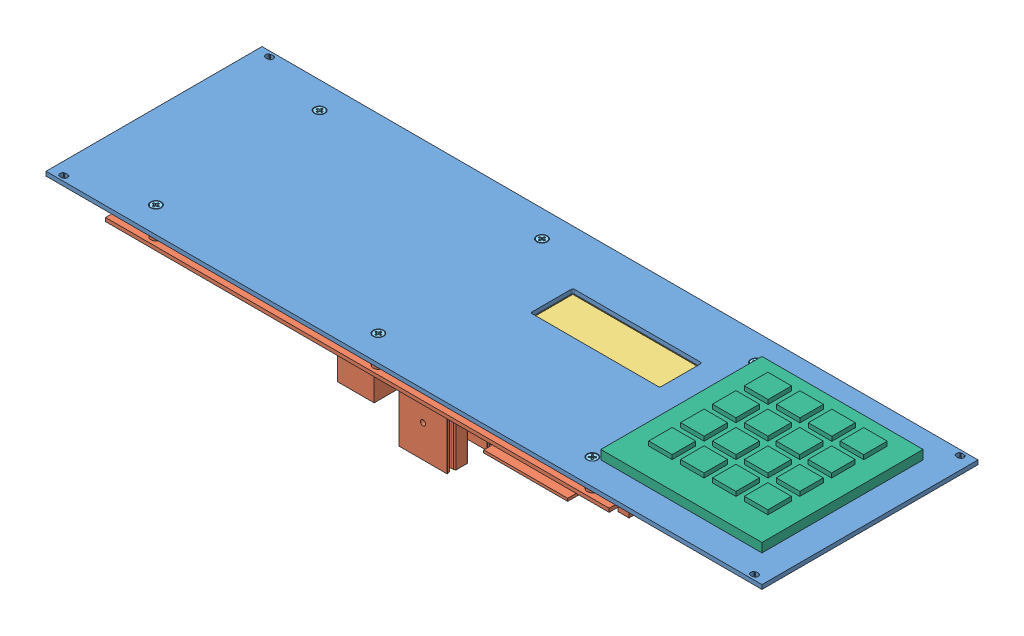
SolidWorks assembly MLA-0387-M5, configuration Default. Lengths in mm.
Overall size (426.52 64.16 128.7).
14 component instances, 6 part files, 28 mates.
Components (placement in the parent):
- MLA-0387-M1-1: MLA-0387-M1 [Default] at (-31.2027 -157.9839 598.0559) size (426.52 2.5 128.7)
- MLA-0387-P1-PA1-1: MLA-0387-P1-PA1 [Default] at (-3.4827 205.6061 369.0559) x (1 0 0) z (0 1 0) size (300 107.5 53.66)
- WH2004A1-YYH-1: WH2004A1-YYH [Default] at (178.2672 208.6161 325.5559) x (1 0 0.000001) z (0 1 0) size (98 60 10.6)
- pan_head_phillip_M2x4-1: pan_head_phillip_M2x4 [Default] at (180.7673 210.2161 268.0559) x (1 0 0) z (0 0 1) size (4 9.78 4)
- pan_head_phillip_M2x4-2: pan_head_phillip_M2x4 [Default] at (273.7673 210.2161 268.0559) x (1 0 0) z (0 0 1) size (4 9.78 4)
- pan_head_phillip_M2x4-3: pan_head_phillip_M2x4 [Default] at (273.7873 210.2161 323.0559) x (1 0 0) z (0 0 1) size (4 9.78 4)
- pan_head_phillip_M2x4-4: pan_head_phillip_M2x4 [Default] at (180.7673 210.2161 323.0559) x (1 0 0) z (0 0 1) size (4 9.78 4)
- SCREW_ISO 7046-1: SCREW_ISO 7046 [VIJAK M 3x 10] at (21.5173 222.1161 266.5559) x (0 -1 0) z (0 0 1) size (10 5.6 5.6)
- SCREW_ISO 7046-2: SCREW_ISO 7046 [VIJAK M 3x 10] at (21.5173 222.1161 364.0559) x (0 -1 0) z (1 0 0) size (10 5.6 5.6)
- SCREW_ISO 7046-3: SCREW_ISO 7046 [VIJAK M 3x 10] at (154.0173 222.1161 364.0559) x (0 -1 0) z (0 0 1) size (10 5.6 5.6)
- SCREW_ISO 7046-4: SCREW_ISO 7046 [VIJAK M 3x 10] at (154.0173 222.1161 266.5559) x (0 -1 0) z (0 0 1) size (10 5.6 5.6)
- SCREW_ISO 7046-5: SCREW_ISO 7046 [VIJAK M 3x 10] at (281.5173 222.1161 266.5559) x (0 -1 0) z (0 0 1) size (10 5.6 5.6)
- SCREW_ISO 7046-6: SCREW_ISO 7046 [VIJAK M 3x 10] at (281.5173 221.9757 364.0559) x (0 -1 0) z (-0.743067 0 0.669217) size (10 5.6 5.6)
- Storm_7016010-2: Storm_7016010 [Default] at (285.6073 222.1161 363.1059) x (1 0 0) z (0 1 0) size (96 96 22)
Mates (geometry in assembly coordinates):
- Concentric30: concentric aligned: cone of MLA-0387-M1-1 through (21.5173 222.1161 266.5559) axis (0 -1 0); cone of SCREW_ISO 7046-1 through (21.5173 220.6161 266.5559) axis (0 -1 0)
- Coincident48: coincident aligned: plane of MLA-0387-M1-1 through (-23.1223 222.1161 294.98) normal (0 1 0); plane of SCREW_ISO 7046-1 through (21.5173 222.1161 266.5559) normal (0 1 0)
- Concentric31: concentric aligned: cone of MLA-0387-M1-1 through (21.5173 222.1161 364.0559) axis (0 -1 0); cone of SCREW_ISO 7046-2 through (21.5173 220.6161 364.0559) axis (0 -1 0)
- Coincident49: coincident aligned: plane of MLA-0387-M1-1 through (-23.1223 222.1161 294.98) normal (0 1 0); plane of SCREW_ISO 7046-2 through (21.5173 222.1161 364.0559) normal (0 1 0)
- Concentric32: concentric aligned: cone of MLA-0387-M1-1 through (154.0173 222.1161 364.0559) axis (0 -1 0); cone of SCREW_ISO 7046-3 through (154.0173 220.6161 364.0559) axis (0 -1 0)
- Coincident50: coincident aligned: plane of MLA-0387-M1-1 through (-23.1223 222.1161 294.98) normal (0 1 0); plane of SCREW_ISO 7046-3 through (154.0173 222.1161 364.0559) normal (0 1 0)
- Concentric33: concentric aligned: cone of MLA-0387-M1-1 through (154.0173 222.1161 266.5559) axis (0 -1 0); cone of SCREW_ISO 7046-4 through (154.0173 220.6161 266.5559) axis (0 -1 0)
- Coincident51: coincident aligned: plane of MLA-0387-M1-1 through (-23.1223 222.1161 294.98) normal (0 1 0); plane of SCREW_ISO 7046-4 through (154.0173 222.1161 266.5559) normal (0 1 0)
- Concentric34: concentric aligned: cone of MLA-0387-M1-1 through (281.5173 222.1161 266.5559) axis (0 -1 0); cone of SCREW_ISO 7046-5 through (281.5173 220.6161 266.5559) axis (0 -1 0)
- Coincident52: coincident aligned: plane of MLA-0387-M1-1 through (-23.1223 222.1161 294.98) normal (0 1 0); plane of SCREW_ISO 7046-5 through (281.5173 222.1161 266.5559) normal (0 1 0)
- Coincident53: coincident: circle of MLA-0387-M1-1; cone of SCREW_ISO 7046-6 through (281.5173 220.4757 364.0559) axis (0 -1 0)
- Concentric36: concentric aligned: cylinder of MLA-0387-M1-1 through (154.0173 222.1161 266.5559) axis (0 -1 0) radius 1.75; cylinder of MLA-0387-P1-PA1-1 through (154.0173 202.0332 266.5559) axis (0 -1 0) radius 1.2295
- Concentric37: concentric aligned: circle of MLA-0387-M1-1; circle of MLA-0387-P1-PA1-1
- Coincident55: coincident anti-aligned: plane of MLA-0387-M1-1 through (-23.1223 219.6161 294.98) normal (0 -1 0); plane of MLA-0387-P1-PA1-1 through (154.0173 219.6161 266.5559) normal (0 1 0)
- Concentric38: concentric aligned: cylinder of MLA-0387-P1-PA1-1 through (180.7673 204.2161 268.0559) axis (0 1 0) radius 2.175; cylinder of WH2004A1-YYH-1 through (180.7672 208.6161 268.0559) axis (0 1 0) radius 1.25
- Coincident57: coincident anti-aligned: plane of MLA-0387-P1-PA1-1 through (180.7673 208.6161 268.0559) normal (0 1 0); plane of WH2004A1-YYH-1 through (178.2672 208.6161 325.5559) normal (0 -1 0)
- Concentric40: concentric anti-aligned: cylinder of MLA-0387-P1-PA1-1 through (226.8672 203.4617 268.0559) axis (0 -1 0) radius 0.55; cylinder of WH2004A1-YYH-1 through (226.8672 208.6161 268.0559) axis (0 1 0) radius 0.5
- Concentric41: concentric anti-aligned: cylinder of MLA-0387-P1-PA1-1 through (180.7673 204.2161 268.0559) axis (0 1 0) radius 2.175; cylinder of pan_head_phillip_M2x4-1 through (180.7673 212.0011 268.0559) axis (0 -1 0) radius 2
- Coincident58: coincident: plane of WH2004A1-YYH-1 through (178.2672 210.2161 325.5559) normal (0 1 0); plane of pan_head_phillip_M2x4-1 through (180.7673 210.2161 268.0559) normal (0 -1 0)
- Concentric42: concentric anti-aligned: cylinder of MLA-0387-P1-PA1-1 through (273.7673 204.2161 268.0559) axis (0 1 0) radius 2.175; cylinder of pan_head_phillip_M2x4-2 through (273.7673 212.0011 268.0559) axis (0 -1 0) radius 2
- Coincident59: coincident: plane of WH2004A1-YYH-1 through (178.2672 210.2161 325.5559) normal (0 1 0); plane of pan_head_phillip_M2x4-2 through (273.7673 210.2161 268.0559) normal (0 -1 0)
- Concentric43: concentric aligned: cylinder of MLA-0387-P1-PA1-1 through (273.7873 201.0527 323.0559) axis (0 -1 0) radius 0.7835; cylinder of pan_head_phillip_M2x4-3 through (273.7873 212.0011 323.0559) axis (0 -1 0) radius 2
- Coincident60: coincident: plane of WH2004A1-YYH-1 through (178.2672 210.2161 325.5559) normal (0 1 0); plane of pan_head_phillip_M2x4-3 through (273.7873 210.2161 323.0559) normal (0 -1 0)
- Concentric44: concentric aligned: cylinder of MLA-0387-P1-PA1-1 through (180.7673 201.0527 323.0559) axis (0 -1 0) radius 0.7835; cylinder of pan_head_phillip_M2x4-4 through (180.7673 212.0011 323.0559) axis (0 -1 0) radius 2
- Coincident61: coincident: plane of WH2004A1-YYH-1 through (178.2672 210.2161 325.5559) normal (0 1 0); plane of pan_head_phillip_M2x4-4 through (185.1373 164.3289 325.0217) normal (0 -1 0)
- Concentric45: concentric anti-aligned: cylinder of MLA-0387-M1-1 through (301.6073 222.1161 283.1059) axis (0 -1 0) radius 1.75; cylinder of Storm_7016010-2 through (301.6073 208.1161 283.1059) axis (0 1 0) radius 1.5
- Concentric46: concentric anti-aligned: cylinder of MLA-0387-M1-1 through (365.6073 222.1161 347.1059) axis (0 -1 0) radius 1.75; cylinder of Storm_7016010-2 through (365.6073 208.1161 347.1059) axis (0 1 0) radius 1.5
- Coincident62: coincident anti-aligned: plane of MLA-0387-M1-1 through (-23.1223 222.1161 294.98) normal (0 1 0); plane of Storm_7016010-2 through (285.6073 222.1161 363.1059) normal (0 -1 0)
